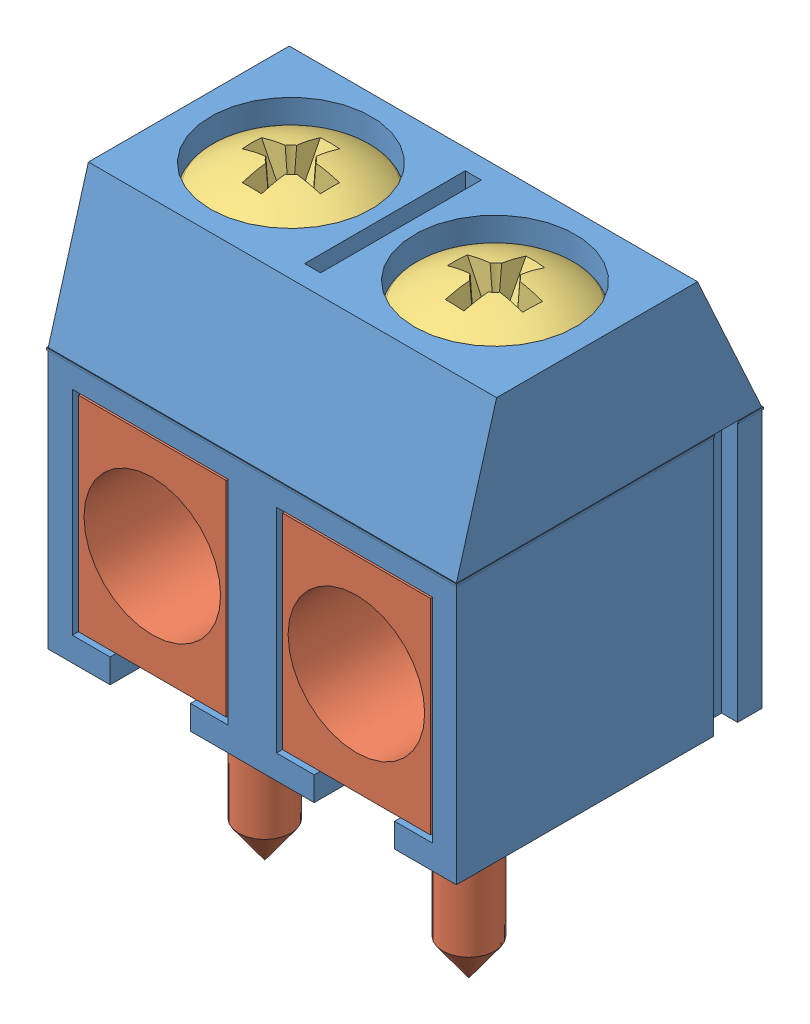
SolidWorks assembly ScrewTerminal_2, configuration Default. Lengths in mm.
Overall size (10.58 14.77 7.64).
5 component instances, 3 part files, 13 mates.
Components (placement in the parent):
- TerminalBlockCasing-1: TerminalBlockCasing [Default] at (-112.9203 -1.2552 55.981) size (10.58 10 7.64)
- TerminalBlockInsert-1: TerminalBlockInsert [Default] at (-118.7003 -0.5552 56.531) size (3.68 10.5 7)
- TerminalBlockInsert-3: TerminalBlockInsert [Default] at (-113.6203 -0.5552 56.531) size (3.68 10.5 7)
- pan head cross recess screw_iso-1: pan head cross recess screw_iso [ISO 7045 - M2 x 3 - Z - 3C] at (-115.4603 8.8448 60.081) x (0 -1 0) z (0.035518 0 -0.999369) size (4.57 4 4)
- pan head cross recess screw_iso-2: pan head cross recess screw_iso [ISO 7045 - M2 x 3 - Z - 3C] at (-120.5403 8.8448 60.081) x (0 -1 0) z (0 0 1) size (4.57 4 4)
Mates (geometry in assembly coordinates):
- Width1: width aligned: plane of TerminalBlockInsert-2 through (-113.8103 4.3948 56.531) normal (1 0 0); plane of TerminalBlockCasing-1 through (-117.6603 4.3948 56.531) normal (-1 0 0); plane of TerminalBlockInsert-2 through (-117.4003 -1.2552 49.4126) normal (1 0 0); plane of TerminalBlockCasing-1 through (-113.5203 -1.2552 49.4126) normal (-1 0 0)
- Width2: width anti-aligned: plane of TerminalBlockInsert-2 through (-113.8103 4.3948 56.531) normal (0 1 0); plane of TerminalBlockCasing-1 through (-113.8103 -0.4052 56.531) normal (0 -1 0); plane of TerminalBlockInsert-2 through (-112.9203 4.6448 49.4126) normal (0 -1 0); plane of TerminalBlockCasing-1 through (-112.9203 -0.6552 49.4126) normal (0 1 0)
- Width3: width anti-aligned: plane of TerminalBlockInsert-1 through (-118.7003 4.5448 56.531) normal (1 0 0); plane of TerminalBlockCasing-1 through (-122.3803 4.5448 56.531) normal (-1 0 0); plane of TerminalBlockInsert-1 through (-118.6003 -1.2552 49.4126) normal (-1 0 0); plane of TerminalBlockCasing-1 through (-122.4803 -1.2552 49.4126) normal (1 0 0)
- Width4: width anti-aligned: plane of TerminalBlockInsert-1 through (-118.7003 4.5448 56.531) normal (0 1 0); plane of TerminalBlockCasing-1 through (-118.7003 -0.5552 56.531) normal (0 -1 0); plane of TerminalBlockInsert-1 through (-112.9203 4.6448 49.4126) normal (0 -1 0); plane of TerminalBlockCasing-1 through (-112.9203 -0.6552 49.4126) normal (0 1 0)
- Width5: width anti-aligned: plane of TerminalBlockCasing-1 through (-112.9203 5.2448 56.481) normal (0 0 1); plane of TerminalBlockInsert-1 through (-112.9203 5.2448 63.581) normal (0 0 1); plane of TerminalBlockCasing-1 through (-118.7003 4.5448 56.531) normal (0 0 -1); plane of TerminalBlockInsert-1 through (-118.7003 4.5448 63.531) normal (0 0 1)
- Width6: width aligned: plane of TerminalBlockCasing-1 through (-112.9203 5.2448 56.481) normal (0 0 1); plane of TerminalBlockInsert-2 through (-112.9203 5.2448 63.581) normal (0 0 1); plane of TerminalBlockCasing-1 through (-113.8103 4.3948 63.531) normal (0 0 1); plane of TerminalBlockInsert-2 through (-113.8103 4.3948 56.531) normal (0 0 -1)
- Width7: width anti-aligned: plane of TerminalBlockInsert-3 through (-113.6203 4.5448 56.531) normal (1 0 0); plane of TerminalBlockCasing-1 through (-117.3003 4.5448 56.531) normal (-1 0 0); plane of TerminalBlockInsert-3 through (-113.5203 -1.2552 49.4126) normal (-1 0 0); plane of TerminalBlockCasing-1 through (-117.4003 -1.2552 49.4126) normal (1 0 0)
- Width8: width anti-aligned: plane of TerminalBlockInsert-3 through (-113.6203 -0.5552 56.531) normal (0 -1 0); plane of TerminalBlockCasing-1 through (-113.6203 4.5448 56.531) normal (0 1 0); plane of TerminalBlockInsert-3 through (-112.9203 -0.6552 49.4126) normal (0 1 0); plane of TerminalBlockCasing-1 through (-112.9203 4.6448 49.4126) normal (0 -1 0)
- Width9: width anti-aligned: plane of TerminalBlockInsert-3 through (-113.6203 4.5448 56.531) normal (0 0 -1); plane of TerminalBlockCasing-1 through (-113.6203 4.5448 63.531) normal (0 0 1); plane of TerminalBlockInsert-3 through (-112.9203 5.2448 56.481) normal (0 0 1); plane of TerminalBlockCasing-1 through (-112.9203 5.2448 63.581) normal (0 0 1)
- Coincident3: coincident aligned: circle of TerminalBlockCasing-1; cylinder of pan head cross recess screw_iso-2 through (-120.5403 34.2448 60.081) axis (0 1 0) radius 1
- Coincident4: coincident aligned: circle of TerminalBlockCasing-1; cylinder of pan head cross recess screw_iso-1 through (-115.4603 34.2448 60.081) axis (0 1 0) radius 1
- Coincident5: coincident anti-aligned: plane of TerminalBlockCasing-1 through (-120.5403 7.2448 60.081) normal (0 1 0); plane of pan head cross recess screw_iso-2 through (-119.5403 7.2448 60.081) normal (0 -1 0)
- Coincident6: coincident anti-aligned: plane of TerminalBlockCasing-1 through (-115.4603 7.2448 60.081) normal (0 1 0); plane of pan head cross recess screw_iso-1 through (-116.4597 7.2448 60.0455) normal (0 -1 0)
